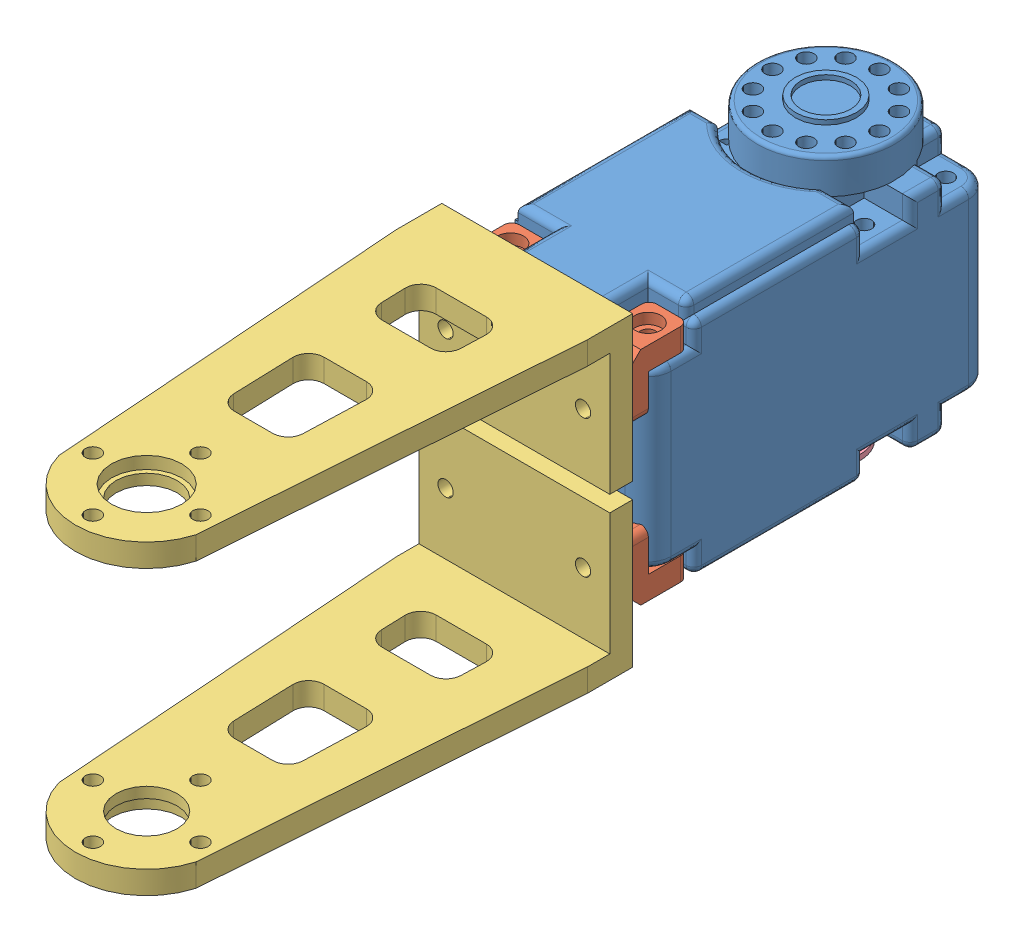
SolidWorks assembly Thigh, configuration Default. Lengths in mm.
Overall size (25 40.1 107.98).
8 component instances, 4 part files, 18 mates.
Components (placement in the parent):
- herkulex_motor-2: herkulex_motor [Default] at (23.0079 4.9835 32.2152) size (24 34.2 45)
- L joint-5: L joint [Default] at (29.4579 30.9835 54.2152) x (0 -1 0) z (0 0 1) size (8.2 5.1 8.2)
- upper leg-2: upper leg [Default] at (23.0079 -14.0665 160.3647) x (0 1 0) z (1 0 0) size (19 60.48 25)
- L joint-6: L joint [Default] at (11.4579 30.9835 54.2152) x (0 -1 0) z (0 0 1) size (8.2 5.1 8.2)
- L joint-7: L joint [Default] at (34.5579 7.9835 54.2152) x (0 1 0) z (0 0 1) size (8.2 5.1 8.2)
- L joint-8: L joint [Default] at (16.5579 7.9835 54.2152) x (0 1 0) z (0 0 1) size (8.2 5.1 8.2)
- upper leg-3: upper leg [Default] at (23.0079 53.0335 160.3647) x (0 -1 0) z (-1 0 0) size (19 60.48 25)
- support-1: support [Default] at (23.0079 5.4835 19.4152) x (0 -1 0) z (-0.265948 0 0.963987) size (5.5 9 9)
Mates (geometry in assembly coordinates):
- Concentric5: concentric anti-aligned: cylinder of herkulex_motor-2 through (32.0079 4.9835 51.7152) axis (0 1 0) radius 1; cylinder of L joint-5 through (32.0079 36.0835 51.7152) axis (0 -1 0) radius 1
- Coincident9: coincident anti-aligned: plane of herkulex_motor-2 through (23.0079 30.9835 32.2152) normal (0 1 0); plane of L joint-5 through (34.5579 30.9835 54.2152) normal (0 -1 0)
- Concentric6: concentric anti-aligned: cylinder of herkulex_motor-2 through (14.0079 4.9835 51.7152) axis (0 1 0) radius 1; cylinder of L joint-6 through (14.0079 36.0835 51.7152) axis (0 -1 0) radius 1
- Coincident10: coincident anti-aligned: plane of herkulex_motor-2 through (23.0079 30.9835 32.2152) normal (0 1 0); plane of L joint-6 through (16.5579 30.9835 54.2152) normal (0 -1 0)
- Concentric7: concentric anti-aligned: cylinder of herkulex_motor-2 through (32.0079 4.9835 51.7152) axis (0 1 0) radius 1; cylinder of L joint-7 through (32.0079 6.3835 51.7152) axis (0 -1 0) radius 1.7
- Parallel5: parallel aligned: plane of herkulex_motor-2 through (11.0079 35.9835 54.7152) normal (0 0 1); plane of L joint-7 through (29.4579 4.9835 57.2152) normal (0 0 1)
- Coincident12: coincident anti-aligned: plane of herkulex_motor-2 through (23.0079 7.9835 32.2152) normal (0 -1 0); plane of L joint-7 through (29.4579 7.9835 54.2152) normal (0 1 0)
- Concentric8: concentric aligned: cylinder of herkulex_motor-2 through (14.0079 4.9835 51.7152) axis (0 1 0) radius 1; cylinder of L joint-8 through (14.0079 2.8835 51.7152) axis (0 1 0) radius 1
- Coincident13: coincident anti-aligned: plane of herkulex_motor-2 through (23.0079 7.9835 32.2152) normal (0 -1 0); plane of L joint-8 through (11.4579 7.9835 54.2152) normal (0 1 0)
- Parallel6: parallel aligned: plane of herkulex_motor-2 through (11.0079 35.9835 54.7152) normal (0 0 1); plane of L joint-8 through (11.4579 4.9835 57.2152) normal (0 0 1)
- Coincident15: coincident anti-aligned: plane of upper leg-2 through (10.5079 61.6219 57.2152) normal (0 0 -1); plane of L joint-7 through (29.4579 4.9835 57.2152) normal (0 0 1)
- Coincident16: coincident anti-aligned: cylinder of upper leg-2 through (32.0079 10.4835 48.7152) axis (0 0 1) radius 1; circle of L joint-7
- Parallel7: parallel aligned: plane of herkulex_motor-2 through (23.0079 4.9835 32.2152) normal (0 -1 0); plane of upper leg-2 through (23.0079 -0.5665 160.3647) normal (0 -1 0)
- Coincident18: coincident anti-aligned: plane of L joint-5 through (34.5579 33.9835 57.2152) normal (0 0 1); plane of upper leg-3 through (35.5079 -22.6549 57.2152) normal (0 0 -1)
- Concentric9: concentric anti-aligned: cylinder of L joint-5 through (32.0079 28.4835 59.3152) axis (0 0 -1) radius 1; cylinder of upper leg-3 through (32.0079 28.4835 48.7152) axis (0 0 1) radius 1
- Parallel8: parallel aligned: plane of herkulex_motor-2 through (23.0079 35.9835 32.2152) normal (0 1 0); plane of upper leg-3 through (23.0079 39.5335 160.3647) normal (0 1 0)
- Coincident19: coincident anti-aligned: plane of herkulex_motor-2 through (23.0079 5.4835 19.4152) normal (0 -1 0); plane of support-1 through (23.0079 5.4835 19.4152) normal (0 1 0)
- Concentric10: concentric aligned: cylinder of herkulex_motor-2 through (23.0079 14.9835 19.4152) axis (0 -1 0) radius 1.475; cylinder of support-1 through (23.0079 1.9835 19.4152) axis (0 -1 0) radius 2.7
